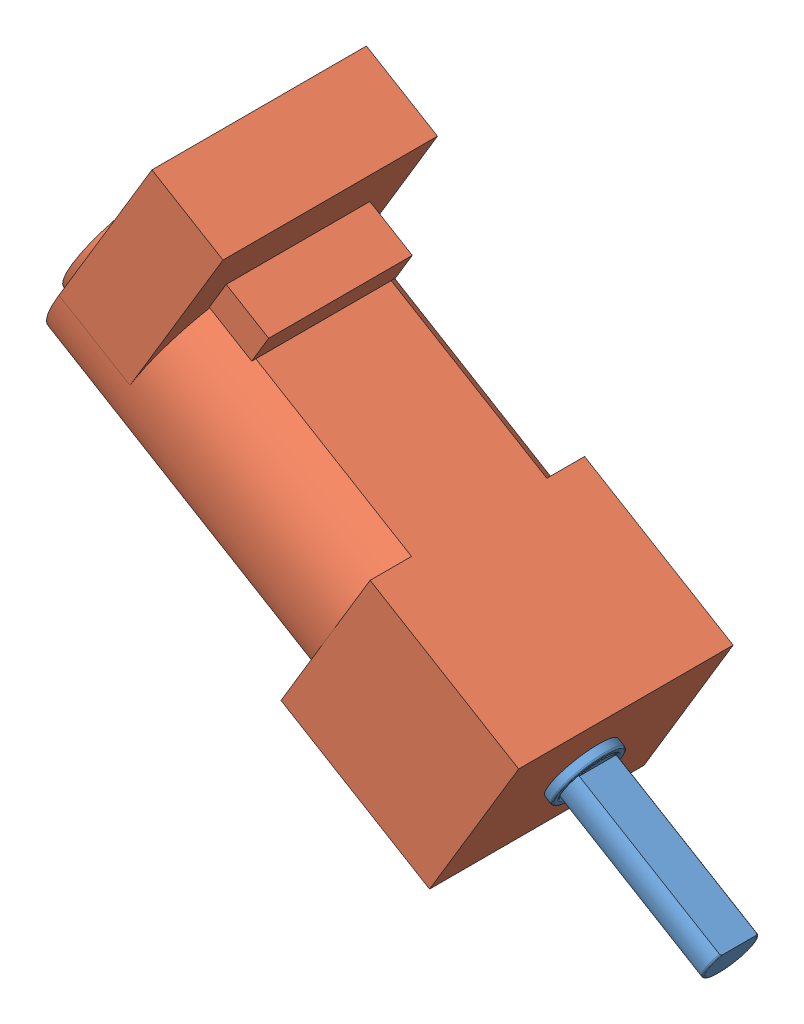
SolidWorks assembly motor_cav, configuration Default. Lengths in mm.
Overall size (42.79 35.05 13).
2 component instances, 2 part files, 3 mates.
Components (placement in the parent):
- N20.sat-1: N20.sat [Default] at (-89.5914 81.3033 -206.3892) x (-0.857627 0.514272 0) z (0.514272 0.857627 0) size (40.8 12 16)
- motor_cav_tolerances-1: motor_cav_tolerances [Default] at (22.2922 21.9688 25.3175) x (0 0 -1) z (0.857627 -0.514272 0) size (13 16.51 30.5)
Mates (geometry in assembly coordinates):
- Width3: width = 0.25 mm: plane of motor_cav_tolerances-1 through (8.999 29.94 25.3175) normal (-0.857627 0.514272 0); plane of N20.sat-1 through (10.2854 29.1686 25.3175) normal (0.857627 -0.514272 0); plane of motor_cav_tolerances-1 through (11.8902 34.2754 25.3175) normal (-0.857627 0.514272 0); plane of N20.sat-1 through (12.7478 33.7611 25.3175) normal (0.857627 -0.514272 0)
- Width4: width anti-aligned: plane of motor_cav_tolerances-1 through (15.9218 38.5682 25.3175) normal (0.514272 0.857627 0); plane of N20.sat-1 through (28.0142 12.0662 31.8175) normal (-0.514272 -0.857627 0); plane of motor_cav_tolerances-1 through (10.7784 22.6989 25.3175) normal (-0.514272 -0.857627 0); plane of N20.sat-1 through (15.1475 38.7352 25.3175) normal (0.514272 0.857627 0)
- Width5: width anti-aligned: plane of motor_cav_tolerances-1 through (10.2854 29.1686 31.8175) normal (0 0 1); plane of N20.sat-1 through (10.2854 29.1686 18.8175) normal (0 0 -1); plane of motor_cav_tolerances-1 through (12.319 34.0182 19.3175) normal (0 0 -1); plane of N20.sat-1 through (12.319 34.0182 31.3175) normal (0 0 1)
